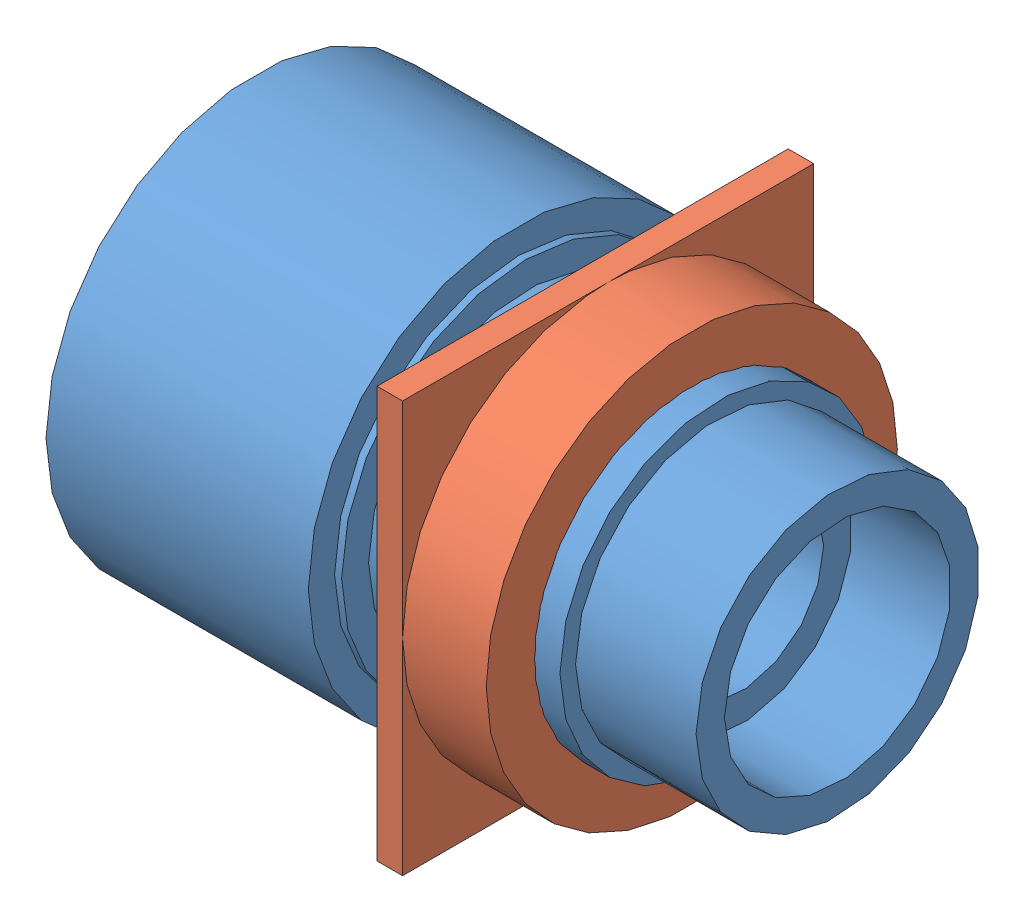
SolidWorks assembly A22L_GR, configuration Default. Lengths in mm.
Overall size (41 29.7 29.7).
4 component instances, 4 part files, 9 mates.
Components (placement in the parent):
- A22L_GR_BASE-1: A22L_GR_BASE [Default] at origin size (41 29.7 29.7)
- A22L_GR_NUTS-1: A22L_GR_NUTS [Default] at (4 0 0) size (7.7 29 29)
- A22Z_30TR-1: A22Z_30TR [Default] at (-19 0 0) size (10.2 23.4 23.4)
- A22Z_3490-1: A22Z_3490 [Default] at (-11.8 0 0) size (5.2 19.6 19.6)
Mates (geometry in assembly coordinates):
- Concentric1: concentric: cylinder of A22L_GR_BASE-1 through (-84.7961 0 0) axis (-1 0 0) radius 11.1; cylinder of A22L_GR_NUTS-1 through (4 0 0) axis (1 0 0) radius 11.1
- Parallel1: parallel: plane of A22L_GR_BASE-1; plane of A22L_GR_NUTS-1
- Distance1: distance = 4 mm: plane of A22L_GR_BASE-1 through (0 13 0) normal (1 0 0); plane of A22L_GR_NUTS-1 through (4 0 0) normal (-1 0 0)
- Concentric2: concentric: cylinder of A22L_GR_BASE-1 through (-84.7961 0 0) axis (-1 0 0) radius 8.95; cylinder of A22Z_3490-1 through (-21.66 0 0) axis (-1 0 0) radius 8.95
- Parallel2: parallel: plane of A22L_GR_BASE-1; plane of A22Z_3490-1
- Coincident1: coincident: plane of A22L_GR_BASE-1 through (-11.8 11 0) normal (-1 0 0); plane of A22Z_3490-1 through (-11.8 9.8 0) normal (1 0 0)
- Concentric3: concentric: cylinder of A22L_GR_BASE-1 through (-84.7961 0 0) axis (-1 0 0) radius 11; cylinder of A22Z_30TR-1 through (-11.8 0 0) axis (1 0 0) radius 11
- Parallel3: parallel: plane of A22L_GR_BASE-1; plane of A22Z_30TR-1
- Coincident2: coincident: plane of A22L_GR_BASE-1 through (-19 0 0) normal (-1 0 0); plane of A22Z_30TR-1 through (-19 0 0) normal (-1 0 0)
